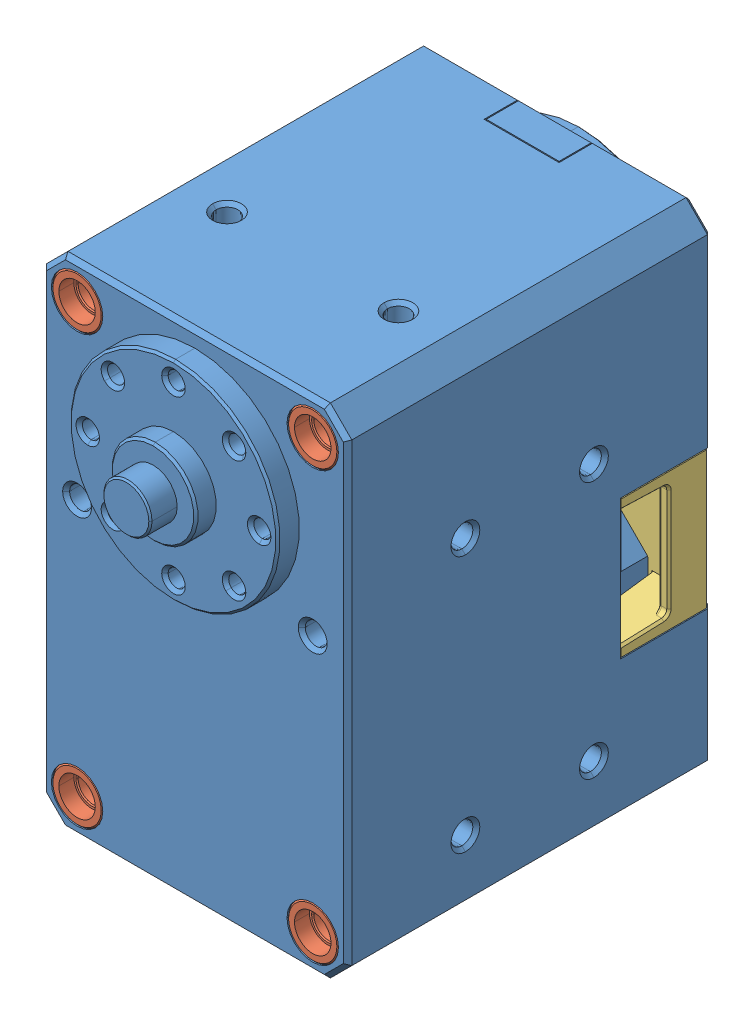
SolidWorks assembly x-430_idle, configuration Default. Lengths in mm.
Overall size (28.5 46.5 42.4).
10 component instances, 3 part files, 0 mates.
Components (placement in the parent):
- X-430_IDLE.stp-1: X-430_IDLE.stp [Default] at origin size (28.5 46.5 42.4)
- X-430_SPACER_RING.stp-1: X-430_SPACER_RING.stp [Default] at (11 8 14.2) x (-1 0 0) z (0 1 0) size (4.8 2.8 4.8)
- X-430_SPACER_RING.stp-2: X-430_SPACER_RING.stp [Default] at (-11 8 14.2) x (-1 0 0) z (0 1 0) size (4.8 2.8 4.8)
- X-430_SPACER_RING.stp-3: X-430_SPACER_RING.stp [Default] at (11 -32 14.2) x (-1 0 0) z (0 1 0) size (4.8 2.8 4.8)
- X-430_SPACER_RING.stp-4: X-430_SPACER_RING.stp [Default] at (-11 -32 14.2) x (-1 0 0) z (0 1 0) size (4.8 2.8 4.8)
- X-430_SPACER_RING.stp-5: X-430_SPACER_RING.stp [Default] at (-11 8 -14.2) x (1 0 0) z (0 1 0) size (4.8 2.8 4.8)
- X-430_SPACER_RING.stp-6: X-430_SPACER_RING.stp [Default] at (11 8 -14.2) x (1 0 0) z (0 1 0) size (4.8 2.8 4.8)
- X-430_SPACER_RING.stp-7: X-430_SPACER_RING.stp [Default] at (-11 -32 -14.2) x (1 0 0) z (0 1 0) size (4.8 2.8 4.8)
- X-430_SPACER_RING.stp-8: X-430_SPACER_RING.stp [Default] at (11 -32 -14.2) x (1 0 0) z (0 1 0) size (4.8 2.8 4.8)
- X-430_CVR_CABLE.stp-1: X-430_CVR_CABLE.stp [Default] at origin size (28.5 12.8 8.8)
